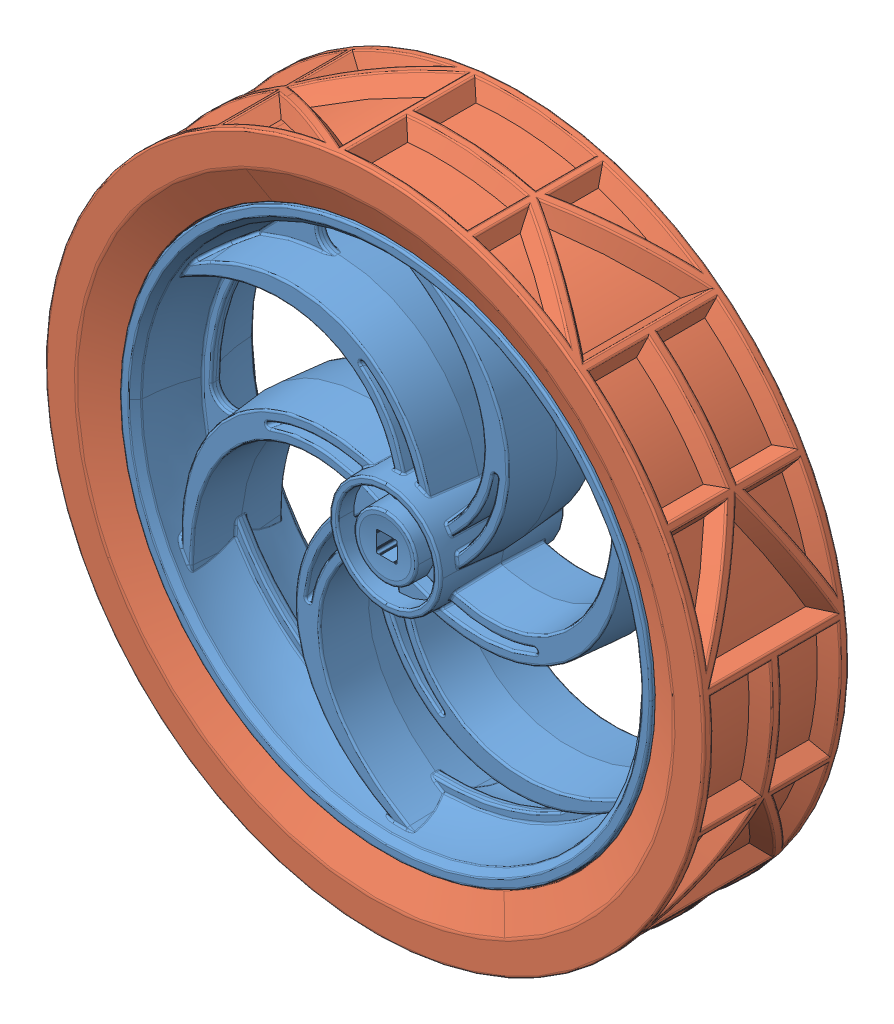
SolidWorks assembly 4_Wheel_276-1497, configuration Default. Lengths in mm.
Overall size (172.06 209.49 22.31).
3 component instances, 2 part files, 0 mates.
Components (placement in the parent):
- 4_Wheel_276-1497.STEP-1: 4_Wheel_276-1497.STEP [Default] at origin size (172.06 209.49 22.31)
  - MEDIUM-WHEEL-HUB.STEP-1: MEDIUM-WHEEL-HUB.STEP [Default] at (-37.6569 24.2609 3.3885) size (158.78 162.66 19.72)
  - MEDIUM-WHEEL-TIRE.STEP-1: MEDIUM-WHEEL-TIRE.STEP [Default] at (-37.6569 24.2609 3.3885) x (-0.900891 -0.434045 0) z (-0.434045 0.900891 0) size (102.82 22.31 183)
